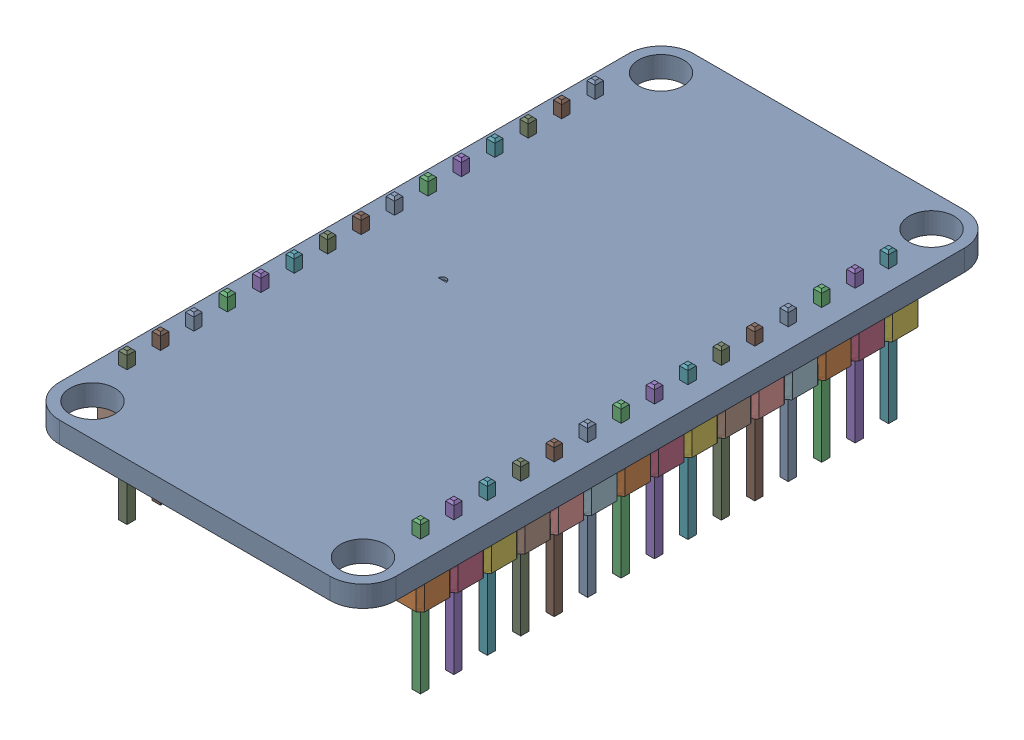
SolidWorks assembly Placa Base, configuration Default. Lengths in mm.
Overall size (25.55 11.43 48.19).
93 component instances, 5 part files, 0 mates.
Components (placement in the parent):
- Placa Base-1: Placa Base [Default] at origin size (25.55 1.6 48.19)
- Pin Header 1x15 TH Pitch 2.54mm v3 v1-1: Pin Header 1x15 TH Pitch 2.54mm v3 v1 [Default] at (24.996 0.1484 -10.5049) x (0 0 -1) z (0 1 0) size (38.1 2.59 11.43)
  - asm_pin-1: asm_pin [Default] at (-4.318 1.27 0.0014) x (1 0 0) z (0 0 -1) size (2.54 2.59 11.43)
    - spacer-1: spacer [Default] at origin size (2.54 2.59 2.54)
    - pin-1: pin [Default] at origin size (0.64 0.64 11.43)
  - asm_pin_1-1: asm_pin_1 [Default] at (-1.778 1.27 0.0014) x (1 0 0) z (0 0 -1) size (2.54 2.59 11.43)
    - spacer-1: spacer [Default] at origin size (2.54 2.59 2.54)
    - pin-1: pin [Default] at origin size (0.64 0.64 11.43)
  - asm_pin_2-1: asm_pin_2 [Default] at (0.762 1.27 0.0014) x (1 0 0) z (0 0 -1) size (2.54 2.59 11.43)
    - spacer-1: spacer [Default] at origin size (2.54 2.59 2.54)
    - pin-1: pin [Default] at origin size (0.64 0.64 11.43)
  - asm_pin_3-1: asm_pin_3 [Default] at (3.302 1.27 0.0014) x (1 0 0) z (0 0 -1) size (2.54 2.59 11.43)
    - spacer-1: spacer [Default] at origin size (2.54 2.59 2.54)
    - pin-1: pin [Default] at origin size (0.64 0.64 11.43)
  - asm_pin_4-1: asm_pin_4 [Default] at (5.842 1.27 0.0014) x (1 0 0) z (0 0 -1) size (2.54 2.59 11.43)
    - spacer-1: spacer [Default] at origin size (2.54 2.59 2.54)
    - pin-1: pin [Default] at origin size (0.64 0.64 11.43)
  - asm_pin_5-1: asm_pin_5 [Default] at (8.382 1.27 0.0014) x (1 0 0) z (0 0 -1) size (2.54 2.59 11.43)
    - spacer-1: spacer [Default] at origin size (2.54 2.59 2.54)
    - pin-1: pin [Default] at origin size (0.64 0.64 11.43)
  - asm_pin_6-1: asm_pin_6 [Default] at (10.922 1.27 0.0014) x (1 0 0) z (0 0 -1) size (2.54 2.59 11.43)
    - spacer-1: spacer [Default] at origin size (2.54 2.59 2.54)
    - pin-1: pin [Default] at origin size (0.64 0.64 11.43)
  - asm_pin_7-1: asm_pin_7 [Default] at (13.462 1.27 0.0014) x (1 0 0) z (0 0 -1) size (2.54 2.59 11.43)
    - spacer-1: spacer [Default] at origin size (2.54 2.59 2.54)
    - pin-1: pin [Default] at origin size (0.64 0.64 11.43)
  - asm_pin_8-1: asm_pin_8 [Default] at (16.002 1.27 0.0014) x (1 0 0) z (0 0 -1) size (2.54 2.59 11.43)
    - spacer-1: spacer [Default] at origin size (2.54 2.59 2.54)
    - pin-1: pin [Default] at origin size (0.64 0.64 11.43)
  - asm_pin_9-1: asm_pin_9 [Default] at (18.542 1.27 0.0014) x (1 0 0) z (0 0 -1) size (2.54 2.59 11.43)
    - spacer-1: spacer [Default] at origin size (2.54 2.59 2.54)
    - pin-1: pin [Default] at origin size (0.64 0.64 11.43)
  - asm_pin_10-1: asm_pin_10 [Default] at (21.082 1.27 0.0014) x (1 0 0) z (0 0 -1) size (2.54 2.59 11.43)
    - spacer-1: spacer [Default] at origin size (2.54 2.59 2.54)
    - pin-1: pin [Default] at origin size (0.64 0.64 11.43)
  - asm_pin_11-1: asm_pin_11 [Default] at (23.622 1.27 0.0014) x (1 0 0) z (0 0 -1) size (2.54 2.59 11.43)
    - spacer-1: spacer [Default] at origin size (2.54 2.59 2.54)
    - pin-1: pin [Default] at origin size (0.64 0.64 11.43)
  - asm_pin_12-1: asm_pin_12 [Default] at (26.1619 1.27 0.0014) x (1 0 0) z (0 0 -1) size (2.54 2.59 11.43)
    - spacer-1: spacer [Default] at origin size (2.54 2.59 2.54)
    - pin-1: pin [Default] at origin size (0.64 0.64 11.43)
  - asm_pin_13-1: asm_pin_13 [Default] at (28.702 1.27 0.0014) x (1 0 0) z (0 0 -1) size (2.54 2.59 11.43)
    - spacer-1: spacer [Default] at origin size (2.54 2.59 2.54)
    - pin-1: pin [Default] at origin size (0.64 0.64 11.43)
  - asm_pin_14-1: asm_pin_14 [Default] at (31.242 1.27 0.0014) x (1 0 0) z (0 0 -1) size (2.54 2.59 11.43)
    - spacer-1: spacer [Default] at origin size (2.54 2.59 2.54)
    - pin-1: pin [Default] at origin size (0.64 0.64 11.43)
- Pin Header 1x15 TH Pitch 2.54mm v3 v1 (1) (1)-1: Pin Header 1x15 TH Pitch 2.54mm v3 v1 (1) (1) [Default] at (2.7074 0.1484 -10.5049) x (0 0 -1) z (0 1 0) size (38.1 2.59 11.43)
  - asm_pin (1) (1)-1: asm_pin (1) (1) [Default] at (-4.318 1.27 0.0014) x (1 0 0) z (0 0 -1) size (2.54 2.59 11.43)
    - spacer (1) (1)-1: spacer (1) (1) [Default] at origin size (2.54 2.59 2.54)
    - pin (1) (1)-1: pin (1) (1) [Default] at origin size (0.64 0.64 11.43)
  - asm_pin (1) (1)_1-1: asm_pin (1) (1)_1 [Default] at (-1.778 1.27 0.0014) x (1 0 0) z (0 0 -1) size (2.54 2.59 11.43)
    - spacer (1) (1)-1: spacer (1) (1) [Default] at origin size (2.54 2.59 2.54)
    - pin (1) (1)-1: pin (1) (1) [Default] at origin size (0.64 0.64 11.43)
  - asm_pin (1) (1)_2-1: asm_pin (1) (1)_2 [Default] at (0.762 1.27 0.0014) x (1 0 0) z (0 0 -1) size (2.54 2.59 11.43)
    - spacer (1) (1)-1: spacer (1) (1) [Default] at origin size (2.54 2.59 2.54)
    - pin (1) (1)-1: pin (1) (1) [Default] at origin size (0.64 0.64 11.43)
  - asm_pin (1) (1)_3-1: asm_pin (1) (1)_3 [Default] at (3.302 1.27 0.0014) x (1 0 0) z (0 0 -1) size (2.54 2.59 11.43)
    - spacer (1) (1)-1: spacer (1) (1) [Default] at origin size (2.54 2.59 2.54)
    - pin (1) (1)-1: pin (1) (1) [Default] at origin size (0.64 0.64 11.43)
  - asm_pin (1) (1)_4-1: asm_pin (1) (1)_4 [Default] at (5.842 1.27 0.0014) x (1 0 0) z (0 0 -1) size (2.54 2.59 11.43)
    - spacer (1) (1)-1: spacer (1) (1) [Default] at origin size (2.54 2.59 2.54)
    - pin (1) (1)-1: pin (1) (1) [Default] at origin size (0.64 0.64 11.43)
  - asm_pin (1) (1)_5-1: asm_pin (1) (1)_5 [Default] at (8.382 1.27 0.0014) x (1 0 0) z (0 0 -1) size (2.54 2.59 11.43)
    - spacer (1) (1)-1: spacer (1) (1) [Default] at origin size (2.54 2.59 2.54)
    - pin (1) (1)-1: pin (1) (1) [Default] at origin size (0.64 0.64 11.43)
  - asm_pin (1) (1)_6-1: asm_pin (1) (1)_6 [Default] at (10.922 1.27 0.0014) x (1 0 0) z (0 0 -1) size (2.54 2.59 11.43)
    - spacer (1) (1)-1: spacer (1) (1) [Default] at origin size (2.54 2.59 2.54)
    - pin (1) (1)-1: pin (1) (1) [Default] at origin size (0.64 0.64 11.43)
  - asm_pin (1) (1)_7-1: asm_pin (1) (1)_7 [Default] at (13.462 1.27 0.0014) x (1 0 0) z (0 0 -1) size (2.54 2.59 11.43)
    - spacer (1) (1)-1: spacer (1) (1) [Default] at origin size (2.54 2.59 2.54)
    - pin (1) (1)-1: pin (1) (1) [Default] at origin size (0.64 0.64 11.43)
  - asm_pin (1) (1)_8-1: asm_pin (1) (1)_8 [Default] at (16.002 1.27 0.0014) x (1 0 0) z (0 0 -1) size (2.54 2.59 11.43)
    - spacer (1) (1)-1: spacer (1) (1) [Default] at origin size (2.54 2.59 2.54)
    - pin (1) (1)-1: pin (1) (1) [Default] at origin size (0.64 0.64 11.43)
  - asm_pin (1) (1)_9-1: asm_pin (1) (1)_9 [Default] at (18.542 1.27 0.0014) x (1 0 0) z (0 0 -1) size (2.54 2.59 11.43)
    - spacer (1) (1)-1: spacer (1) (1) [Default] at origin size (2.54 2.59 2.54)
    - pin (1) (1)-1: pin (1) (1) [Default] at origin size (0.64 0.64 11.43)
  - asm_pin (1) (1)_10-1: asm_pin (1) (1)_10 [Default] at (21.082 1.27 0.0014) x (1 0 0) z (0 0 -1) size (2.54 2.59 11.43)
    - spacer (1) (1)-1: spacer (1) (1) [Default] at origin size (2.54 2.59 2.54)
    - pin (1) (1)-1: pin (1) (1) [Default] at origin size (0.64 0.64 11.43)
  - asm_pin (1) (1)_11-1: asm_pin (1) (1)_11 [Default] at (23.622 1.27 0.0014) x (1 0 0) z (0 0 -1) size (2.54 2.59 11.43)
    - spacer (1) (1)-1: spacer (1) (1) [Default] at origin size (2.54 2.59 2.54)
    - pin (1) (1)-1: pin (1) (1) [Default] at origin size (0.64 0.64 11.43)
  - asm_pin (1) (1)_12-1: asm_pin (1) (1)_12 [Default] at (26.1619 1.27 0.0014) x (1 0 0) z (0 0 -1) size (2.54 2.59 11.43)
    - spacer (1) (1)-1: spacer (1) (1) [Default] at origin size (2.54 2.59 2.54)
    - pin (1) (1)-1: pin (1) (1) [Default] at origin size (0.64 0.64 11.43)
  - asm_pin (1) (1)_13-1: asm_pin (1) (1)_13 [Default] at (28.702 1.27 0.0014) x (1 0 0) z (0 0 -1) size (2.54 2.59 11.43)
    - spacer (1) (1)-1: spacer (1) (1) [Default] at origin size (2.54 2.59 2.54)
    - pin (1) (1)-1: pin (1) (1) [Default] at origin size (0.64 0.64 11.43)
  - asm_pin (1) (1)_14-1: asm_pin (1) (1)_14 [Default] at (31.242 1.27 0.0014) x (1 0 0) z (0 0 -1) size (2.54 2.59 11.43)
    - spacer (1) (1)-1: spacer (1) (1) [Default] at origin size (2.54 2.59 2.54)
    - pin (1) (1)-1: pin (1) (1) [Default] at origin size (0.64 0.64 11.43)
